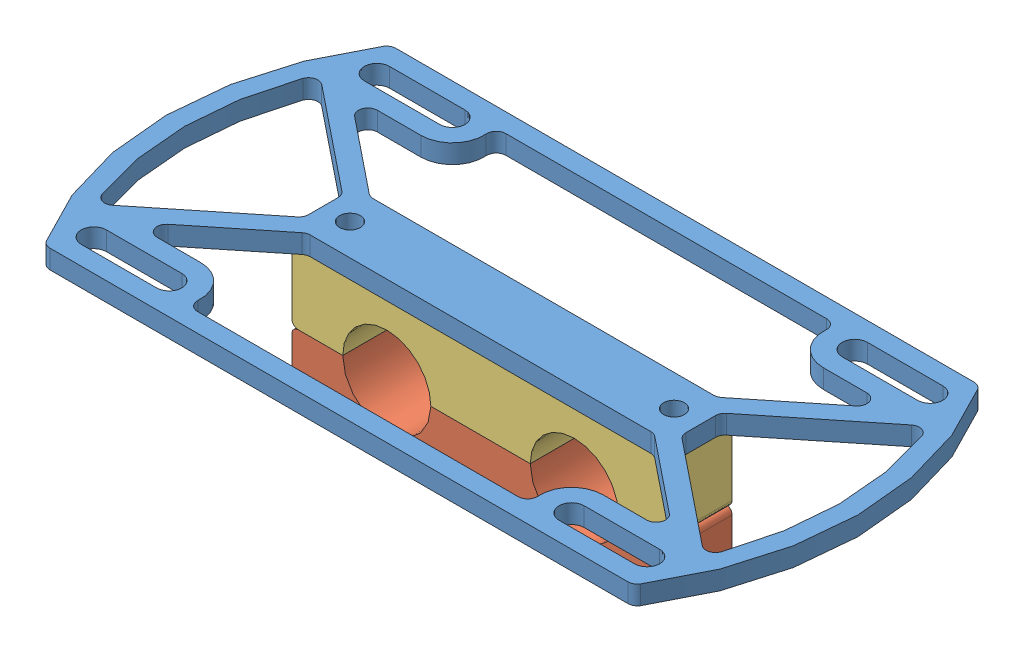
SolidWorks assembly Plate_akk, configuration with screws. Lengths in mm.
Overall size (110 29 55).
6 component instances, 5 part files, 12 mates.
Components (placement in the parent):
- Plate_akk-1: Plate_akk [Default] at (0.1211 -3.6138 -3.1982)
- Scoba_dowble-1: Scoba_dowble [Default] at (25.1211 -14.6138 -25.6982) x (0 1 0) z (-1 0 0)
- Scoba_plate_akk-1: Scoba_plate_akk [По умолчанию] at (-25.6528 -18.1797 346.9469) x (0 1 0) z (-1 0 0)
- socket head cap screw_din_1-3: socket head cap screw_din_1 [DIN 912 M4 x 25 --- 25N] at (80.8711 -26.6637 -30.6982) x (0 1 0) z (0 0 1)
- socket head cap screw_din_1-4: socket head cap screw_din_1 [DIN 912 M4 x 25 --- 25N] at (29.3711 -26.6637 -30.6982) x (0 1 0) z (0 0 1)
- socket button head screw_iso-3: socket button head screw_iso [ISO 7380 - M4 x 16 --- 16N] at (55.1211 -22.8138 -30.6982) x (0 1 0) z (0 0 1)
Mates (geometry in assembly coordinates):
- Совпадение48: coincident anti-aligned: plane of Plate_akk-1 through (0.1211 -3.6138 -3.1982) normal (0 -1 0); plane of Scoba_plate_akk-1 through (85.1211 -3.6138 -25.6982) normal (0 1 0)
- Совпадение49: coincident aligned: plane of Plate_akk-1 through (85.1211 -0.6138 -25.6982) normal (0 0 1); plane of Scoba_plate_akk-1 through (40.2211 -14.6138 -25.6982) normal (0 0 1)
- Совпадение50: coincident aligned: plane of Plate_akk-1 through (85.1211 -0.6138 -35.6982) normal (1 0 0); plane of Scoba_plate_akk-1 through (85.1211 -14.6138 -25.6982) normal (1 0 0)
- Совпадение44: coincident anti-aligned: plane of Scoba_dowble-1 through (62.9211 -14.6138 -35.6982) normal (0 1 0); plane of Scoba_plate_akk-1 through (63.0211 -14.6138 -25.6982) normal (0 -1 0)
- Совпадение45: coincident aligned: plane of Scoba_dowble-1 through (25.1211 -17.6138 -35.6982) normal (-1 0 0); plane of Scoba_plate_akk-1 through (25.1211 -14.6138 -25.6982) normal (-1 0 0)
- Совпадение46: coincident aligned: plane of Scoba_dowble-1 through (40.2211 -14.6138 -35.6982) normal (0 0 -1); plane of Scoba_plate_akk-1 through (40.2211 -14.6138 -35.6982) normal (0 0 -1)
- Концентричный1: concentric aligned: cylinder of Scoba_dowble-1 through (80.8711 -14.6138 -30.6982) axis (0 -1 0) radius 2.25; cylinder of socket head cap screw_din_1-3 through (80.8711 -58.4137 -30.6982) axis (0 -1 0) radius 3.5
- Совпадение51: coincident anti-aligned: plane of Scoba_dowble-1 through (85.1211 -22.6637 -15.3783) normal (0 -1 0); plane of socket head cap screw_din_1-3 through (77.3711 -22.6637 -30.6982) normal (0 1 0)
- Концентричный2: concentric aligned: cylinder of Scoba_dowble-1 through (29.3711 -14.6138 -30.6982) axis (0 -1 0) radius 2.25; cylinder of socket head cap screw_din_1-4 through (29.3711 -58.4137 -30.6982) axis (0 -1 0) radius 3.5
- Совпадение52: coincident anti-aligned: plane of Scoba_dowble-1 through (25.1211 -22.6637 -15.3783) normal (0 -1 0); plane of socket head cap screw_din_1-4 through (25.8711 -22.6637 -30.6982) normal (0 1 0)
- Концентричный3: concentric aligned: cylinder of Scoba_dowble-1 through (55.1211 -14.6138 -30.6982) axis (0 -1 0) radius 2.25; cylinder of socket button head screw_iso-3 through (55.1211 -22.8138 -30.6982) axis (0 -1 0) radius 3.8
- Совпадение53: coincident anti-aligned: plane of Scoba_dowble-1 through (61.8964 -20.6138 -35.6982) normal (0 -1 0); plane of socket button head screw_iso-3 through (53.1211 -20.6138 -30.6982) normal (0 1 0)
